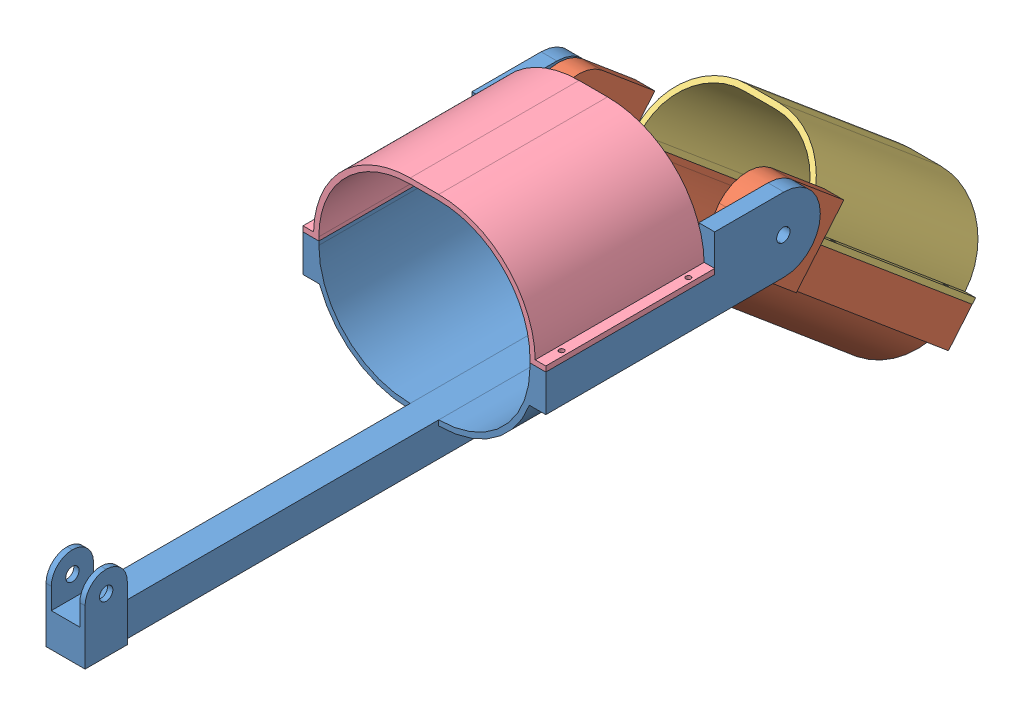
SolidWorks assembly AsmLeg, configuration Default. Lengths in mm.
Overall size (230 319.02 812.95).
4 component instances, 4 part files, 8 mates.
Components (placement in the parent):
- SupDownPart-1: SupDownPart [Default] at (121.8799 276.9922 254.5995) size (230 157 600)
- InfDownPart-1: InfDownPart [Default] at (147.8799 146.8003 28.4612) x (1 0 0) z (0 0.643074 0.765804) size (198 105 300)
- InfSupPart-1: InfSupPart [Default] at (297.8799 246.3548 -55.1384) x (-1 0 0) z (0 0.643074 0.765804) size (180 70 200)
- SupUpPart-1: SupUpPart [Default] at (121.8799 456.9922 414.5995) x (1 0 0) z (0 0 -1) size (230 95 160)
Mates (geometry in assembly coordinates):
- Coincident1: coincident anti-aligned: plane of InfDownPart-1 through (147.8799 325.1923 139.8222) normal (0 0.765804 -0.643074); plane of InfSupPart-1 through (297.8799 325.1923 139.8222) normal (0 -0.765804 0.643074)
- Coincident2: coincident aligned: plane of InfDownPart-1 through (312.8799 275.4151 181.622) normal (1 0 0); plane of InfSupPart-1 through (312.8799 374.9696 98.0224) normal (1 0 0)
- Concentric1: concentric aligned: circle of InfDownPart-1; circle of InfSupPart-1
- Concentric2: concentric anti-aligned: cylinder of SupDownPart-1 through (116.8922 366.9922 189.5995) axis (-1 0 0) radius 6.35; cylinder of InfDownPart-1 through (42.8799 366.9922 189.5995) axis (1 0 0) radius 6.35
- Coincident4: coincident anti-aligned: plane of SupDownPart-1 through (321.8799 276.9922 414.5995) normal (-1 0 0); plane of InfDownPart-1 through (321.8799 146.8003 28.4612) normal (1 0 0)
- Coincident5: coincident anti-aligned: plane of SupDownPart-1 through (121.8799 366.9922 414.5995) normal (0 1 0); plane of SupUpPart-1 through (121.8799 366.9922 254.5995) normal (0 -1 0)
- Coincident6: coincident aligned: plane of SupDownPart-1 through (106.8799 276.9922 414.5995) normal (-1 0 0); plane of SupUpPart-1 through (106.8799 456.9922 254.5995) normal (-1 0 0)
- Coincident7: coincident anti-aligned: cylinder of SupDownPart-1 through (111.886 521.9922 274.5995) axis (0 -1 0) radius 2.3813; circle of SupUpPart-1
